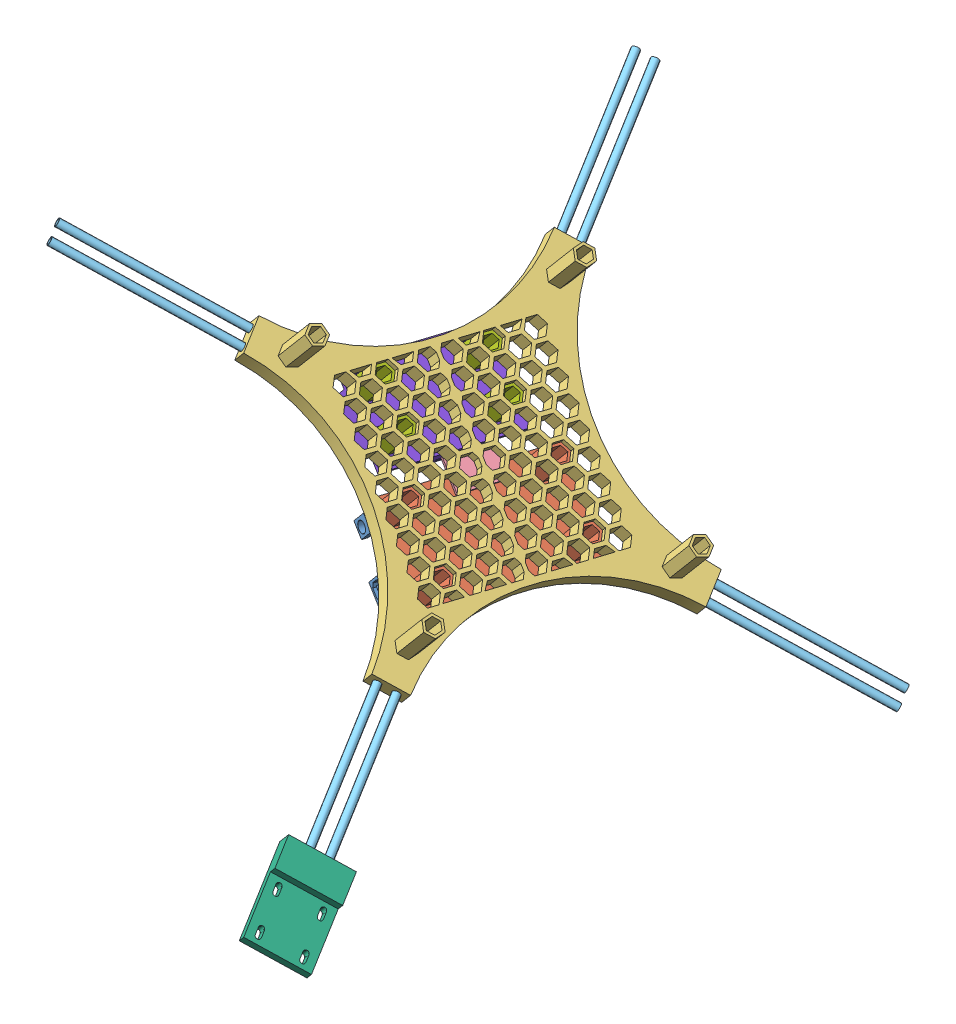
SolidWorks assembly QUAD, configuration Default. Lengths in mm.
Overall size (301.05 238.4 417.1).
19 component instances, 9 part files, 49 mates.
Components (placement in the parent):
- ArduinoMega-1: ArduinoMega [Default] at (337.5166 278.1665 -277.373) x (-0.218735 0.068032 0.97341) z (0.651257 0.753048 0.093714) size (107.95 53.42 12.95)
- arduino_mounting-3: arduino_mounting [Default] at (347.3982 264.798 -221.0032) x (0.218735 -0.068032 -0.97341) z (0.651257 0.753048 0.093714) size (103.6 55.42 18.5)
- krop_test2-1: krop_test2 [Default] at (277.9678 359.392 -375.9096) x (0.726649 -0.654439 0.209025) z (-0.218735 0.068032 0.97341) size (183 40 183)
- gyro_mounting-1: gyro_mounting [Default] at (330.3641 298.6046 -267.5745) x (0.218735 -0.068032 -0.97341) z (0.726649 -0.654439 0.209025) size (25 6.5 18)
- esc_mounting-1: esc_mounting [Default] at (301.4602 334.7052 -340.7941) x (0.726649 -0.654439 0.209025) z (-0.218735 0.068032 0.97341) size (45.02 6 45.46) (hidden)
- carbonfiber_rod-1: carbonfiber_rod [Default] at (475.6624 198.5284 -403.7813) x (0.715923 0.638866 0.281613) z (0.201442 -0.575212 0.792813) size (4.5 115 4.5)
- carbonfiber_rod-2: carbonfiber_rod [Default] at (479.2539 194.3819 -395.4202) x (0.715923 0.638866 0.281613) z (0.201442 -0.575212 0.792813) size (4.5 115 4.5)
- carbonfiber_rod-3: carbonfiber_rod [Default] at (406.2467 220.1183 -94.8694) x (0.91357 0.339343 -0.224132) z (-0.19079 0.84434 0.500689) size (4.5 115 4.5)
- carbonfiber_rod-4: carbonfiber_rod [Default] at (412.9316 215.0097 -100.2745) x (0.91357 0.339343 -0.224132) z (-0.19079 0.84434 0.500689) size (4.5 115 4.5)
- carbonfiber_rod-5: carbonfiber_rod [Default] at (259.2054 363.9466 -228.7662) x (0.715923 0.638866 0.281613) z (0.201442 -0.575212 0.792813) size (4.5 115 4.5)
- carbonfiber_rod-6: carbonfiber_rod [Default] at (262.7969 359.8001 -220.4051) x (0.715923 0.638866 0.281613) z (0.201442 -0.575212 0.792813) size (4.5 115 4.5)
- carbonfiber_rod-7: carbonfiber_rod [Default] at (289.9538 354.3832 -365.6019) x (0.91357 0.339343 -0.224132) z (-0.19079 0.84434 0.500689) size (4.5 115 4.5)
- carbonfiber_rod-8: carbonfiber_rod [Default] at (296.6387 349.2745 -371.0069) x (0.91357 0.339343 -0.224132) z (-0.19079 0.84434 0.500689) size (4.5 115 4.5)
- motor_mounting-1: motor_mounting [Default] at (403.8166 219.6624 -74.3174) x (-0.359149 0.414652 -0.836107) z (0.668488 -0.510864 -0.540502) size (53 10 35)
- ben_til_reciever_mounting-1: ben_til_reciever_mounting [Default] at (295.7926 314.9978 -260.4252) x (0.726649 -0.654439 0.209025) z (-0.218735 0.068032 0.97341) size (12.85 18 14.84)
- ben_til_reciever_mounting-2: ben_til_reciever_mounting [Default] at (277.2873 331.6642 -265.7483) x (0.726649 -0.654439 0.209025) z (-0.218735 0.068032 0.97341) size (12.85 18 14.84)
- ben_til_reciever_mounting-3: ben_til_reciever_mounting [Default] at (308.0725 311.1785 -315.0728) x (0.726649 -0.654439 0.209025) z (-0.218735 0.068032 0.97341) size (12.85 18 14.84)
- ben_til_reciever_mounting-4: ben_til_reciever_mounting [Default] at (289.5672 327.8448 -320.3959) x (0.726649 -0.654439 0.209025) z (-0.218735 0.068032 0.97341) size (12.85 18 14.84)
- reciever_mouting_til_pring-1: reciever_mouting_til_pring [Default] at (265.6062 341.3641 -258.2482) x (0.218735 -0.068032 -0.97341) z (-0.726649 0.654439 -0.209025) size (78.5 12.5 52)
Mates (geometry in assembly coordinates):
- Coincident5: coincident anti-aligned: plane of ArduinoMega-1 through (308.0726 300.3446 -233.3517) normal (0.651257 0.753048 0.093714); plane of arduino_mounting-3 through (347.3982 264.798 -221.0032) normal (-0.651257 -0.753048 -0.093714)
- Distance3: distance = 1 mm: line of ArduinoMega-1 through (329.5183 293.6744 -328.7887) axis (-0.218735 0.068032 0.97341); line of arduino_mounting-3 through (329.7883 294.0189 -333.4325) axis (-0.218735 0.068032 0.97341)
- Distance4: distance = 1 mm: line of ArduinoMega-1 through (358.0369 268.4485 -324.2703) axis (-0.726649 0.654439 -0.209025); line of arduino_mounting-3 through (370.0591 257.7499 -321.8484) axis (-0.726649 0.654439 -0.209025)
- Parallel3: parallel anti-aligned: line of arduino_mounting-3 through (348.375 265.9276 -220.8626) axis (0.218735 -0.068032 -0.97341); line of krop_test2-1 through (361.0536 275.7498 -281.1911) axis (-0.218735 0.068032 0.97341)
- Coincident16: coincident anti-aligned: plane of arduino_mounting-3 through (354.8876 273.4581 -219.9254) normal (0.651257 0.753048 0.093714); plane of krop_test2-1 through (204.8349 415.2808 -316.7784) normal (-0.651257 -0.753048 -0.093714)
- Coincident17: coincident anti-aligned: plane of arduino_mounting-3 through (326.8517 308.9478 -235.5785) normal (0.173894 -0.268302 0.94751); plane of krop_test2-1 through (326.7379 300.0613 -238.074) normal (-0.173894 0.268302 -0.94751)
- Coincident19: coincident anti-aligned: plane of arduino_mounting-3 through (323.7598 312.1159 -239.5493) normal (-0.552755 0.386137 0.738485); plane of krop_test2-1 through (322.2929 303.6765 -236.2345) normal (0.552755 -0.386137 -0.738485)
- Coincident26: coincident anti-aligned: plane of krop_test2-1 through (204.8349 415.2808 -316.7784) normal (-0.651257 -0.753048 -0.093714); plane of gyro_mounting-1 through (331.3409 299.7341 -267.434) normal (0.651257 0.753048 0.093714)
- Parallel5: parallel aligned: line of krop_test2-1 through (329.247 303.381 -282.1875) axis (-0.726649 0.654439 -0.209025); line of gyro_mounting-1 through (335.8324 296.9038 -291.9098) axis (-0.726649 0.654439 -0.209025)
- Coincident31: coincident anti-aligned: plane of krop_test2-1 through (324.9028 305.5925 -269.7678) normal (-0.173894 0.268302 -0.94751); plane of gyro_mounting-1 through (333.7447 304.8148 -271.6107) normal (0.173894 -0.268302 0.94751)
- Coincident32: coincident anti-aligned: plane of krop_test2-1 through (321.7741 308.7983 -273.7859) normal (0.552755 -0.386137 -0.738485); plane of gyro_mounting-1 through (332.3324 305.0815 -263.9396) normal (-0.552755 0.386137 0.738485)
- Coincident44: coincident anti-aligned: plane of krop_test2-1 through (300.1721 335.1058 -335.0617) normal (0.552755 -0.386137 -0.738485); plane of esc_mounting-1 through (300.3665 342.0084 -338.5254) normal (-0.552755 0.386137 0.738485)
- Coincident46: coincident anti-aligned: plane of krop_test2-1 through (304.617 331.4906 -336.9012) normal (-0.173894 0.268302 -0.94751); plane of esc_mounting-1 through (303.4284 338.8711 -334.5932) normal (0.173894 -0.268302 0.94751)
- Coincident47: coincident anti-aligned: plane of krop_test2-1 through (204.8349 415.2808 -316.7784) normal (-0.651257 -0.753048 -0.093714); plane of esc_mounting-1 through (301.4602 334.7052 -340.7941) normal (0.651257 0.753048 0.093714)
- Concentric1: concentric aligned: cylinder of krop_test2-1 through (398.7864 257.2777 -341.6236) axis (0.668488 -0.510864 -0.540502) radius 2.25; cylinder of carbonfiber_rod-1 through (398.7864 257.2777 -341.6236) axis (0.668488 -0.510864 -0.540502) radius 2.25
- Coincident48: coincident anti-aligned: plane of krop_test2-1 through (400.9173 247.2927 -329.5505) normal (0.668488 -0.510864 -0.540502); plane of carbonfiber_rod-1 through (398.7864 257.2777 -341.6236) normal (-0.668488 0.510864 0.540502)
- Concentric2: concentric aligned: cylinder of krop_test2-1 through (402.3778 253.1312 -333.2625) axis (0.668488 -0.510864 -0.540502) radius 2.25; cylinder of carbonfiber_rod-2 through (402.3778 253.1312 -333.2625) axis (0.668488 -0.510864 -0.540502) radius 2.25
- Coincident50: coincident anti-aligned: plane of krop_test2-1 through (400.9173 247.2927 -329.5505) normal (0.668488 -0.510864 -0.540502); plane of carbonfiber_rod-2 through (402.3778 253.1312 -333.2625) normal (-0.668488 0.510864 0.540502)
- Concentric3: concentric aligned: cylinder of krop_test2-1 through (364.9445 267.8033 -191.0218) axis (0.359149 -0.414652 0.836107) radius 2.25; cylinder of carbonfiber_rod-3 through (364.9445 267.8033 -191.0218) axis (0.359149 -0.414652 0.836107) radius 2.25
- Coincident51: coincident anti-aligned: plane of krop_test2-1 through (358.3458 266.5924 -188.7878) normal (0.359149 -0.414652 0.836107); plane of carbonfiber_rod-3 through (364.9445 267.8033 -191.0218) normal (-0.359149 0.414652 -0.836107)
- Concentric4: concentric aligned: cylinder of krop_test2-1 through (371.6294 262.6947 -196.4268) axis (0.359149 -0.414652 0.836107) radius 2.25; cylinder of carbonfiber_rod-4 through (371.6294 262.6947 -196.4268) axis (0.359149 -0.414652 0.836107) radius 2.25
- Coincident52: coincident anti-aligned: plane of krop_test2-1 through (358.3458 266.5924 -188.7878) normal (0.359149 -0.414652 0.836107); plane of carbonfiber_rod-4 through (371.6294 262.6947 -196.4268) normal (-0.359149 0.414652 -0.836107)
- Concentric5: concentric anti-aligned: cylinder of krop_test2-1 through (259.2054 363.9466 -228.7662) axis (-0.668488 0.510864 0.540502) radius 2.25; cylinder of carbonfiber_rod-5 through (182.3293 422.696 -166.6085) axis (0.668488 -0.510864 -0.540502) radius 2.25
- Coincident53: coincident anti-aligned: plane of krop_test2-1 through (254.1534 362.2547 -233.4153) normal (-0.668488 0.510864 0.540502); plane of carbonfiber_rod-5 through (259.2054 363.9466 -228.7662) normal (0.668488 -0.510864 -0.540502)
- Concentric6: concentric anti-aligned: cylinder of krop_test2-1 through (262.7969 359.8001 -220.4051) axis (-0.668488 0.510864 0.540502) radius 2.25; cylinder of carbonfiber_rod-6 through (185.9208 418.5495 -158.2474) axis (0.668488 -0.510864 -0.540502) radius 2.25
- Coincident54: coincident anti-aligned: plane of krop_test2-1 through (254.1534 362.2547 -233.4153) normal (-0.668488 0.510864 0.540502); plane of carbonfiber_rod-6 through (262.7969 359.8001 -220.4051) normal (0.668488 -0.510864 -0.540502)
- Concentric7: concentric anti-aligned: cylinder of krop_test2-1 through (296.6387 349.2745 -371.0069) axis (-0.359149 0.414652 -0.836107) radius 2.25; cylinder of carbonfiber_rod-8 through (255.3365 396.9595 -467.1593) axis (0.359149 -0.414652 0.836107) radius 2.25
- Coincident55: coincident anti-aligned: plane of krop_test2-1 through (296.7248 342.955 -374.178) normal (-0.359149 0.414652 -0.836107); plane of carbonfiber_rod-8 through (296.6387 349.2745 -371.0069) normal (0.359149 -0.414652 0.836107)
- Concentric8: concentric anti-aligned: cylinder of krop_test2-1 through (289.9538 354.3832 -365.6019) axis (-0.359149 0.414652 -0.836107) radius 2.25; cylinder of carbonfiber_rod-7 through (248.6517 402.0682 -461.7542) axis (0.359149 -0.414652 0.836107) radius 2.25
- Coincident56: coincident anti-aligned: plane of krop_test2-1 through (296.7248 342.955 -374.178) normal (-0.359149 0.414652 -0.836107); plane of carbonfiber_rod-7 through (289.9538 354.3832 -365.6019) normal (0.359149 -0.414652 0.836107)
- Coincident58: coincident anti-aligned: plane of krop_test2-1 through (204.8349 415.2808 -316.7784) normal (-0.651257 -0.753048 -0.093714); plane of ben_til_reciever_mounting-1 through (302.9565 323.2813 -259.3943) normal (0.651257 0.753048 0.093714)
- Coincident59: coincident anti-aligned: plane of krop_test2-1 through (306.0183 320.144 -255.4621) normal (-0.726649 0.654439 -0.209025); plane of ben_til_reciever_mounting-1 through (311.2212 325.215 -257.6723) normal (0.726649 -0.654439 0.209025)
- Coincident60: coincident anti-aligned: plane of krop_test2-1 through (301.5733 323.7592 -253.6226) normal (-0.173894 0.268302 -0.94751); plane of ben_til_reciever_mounting-1 through (308.4021 327.1843 -253.906) normal (0.173894 -0.268302 0.94751)
- Coincident61: coincident anti-aligned: plane of krop_test2-1 through (204.8349 415.2808 -316.7784) normal (-0.651257 -0.753048 -0.093714); plane of ben_til_reciever_mounting-2 through (284.4511 339.9477 -264.7175) normal (0.651257 0.753048 0.093714)
- Coincident62: coincident anti-aligned: plane of krop_test2-1 through (287.513 336.8104 -260.7853) normal (-0.726649 0.654439 -0.209025); plane of ben_til_reciever_mounting-2 through (292.7159 341.8814 -262.9955) normal (0.726649 -0.654439 0.209025)
- Coincident63: coincident anti-aligned: plane of krop_test2-1 through (283.068 340.4256 -258.9458) normal (-0.173894 0.268302 -0.94751); plane of ben_til_reciever_mounting-2 through (289.8968 343.8507 -259.2292) normal (0.173894 -0.268302 0.94751)
- Coincident64: coincident anti-aligned: plane of krop_test2-1 through (204.8349 415.2808 -316.7784) normal (-0.651257 -0.753048 -0.093714); plane of ben_til_reciever_mounting-3 through (315.2364 319.462 -314.0419) normal (0.651257 0.753048 0.093714)
- Coincident65: coincident anti-aligned: plane of krop_test2-1 through (319.6145 315.9153 -315.9673) normal (-0.726649 0.654439 -0.209025); plane of ben_til_reciever_mounting-3 through (323.5011 321.3957 -312.3199) normal (0.726649 -0.654439 0.209025)
- Coincident66: coincident anti-aligned: plane of krop_test2-1 through (318.2982 316.3247 -310.1097) normal (-0.173894 0.268302 -0.94751); plane of ben_til_reciever_mounting-3 through (320.682 323.365 -308.5536) normal (0.173894 -0.268302 0.94751)
- Coincident67: coincident anti-aligned: plane of krop_test2-1 through (204.8349 415.2808 -316.7784) normal (-0.651257 -0.753048 -0.093714); plane of ben_til_reciever_mounting-4 through (296.731 336.1284 -319.3651) normal (0.651257 0.753048 0.093714)
- Coincident68: coincident anti-aligned: plane of krop_test2-1 through (301.1091 332.5817 -321.2904) normal (-0.726649 0.654439 -0.209025); plane of ben_til_reciever_mounting-4 through (304.9957 338.0621 -317.6431) normal (0.726649 -0.654439 0.209025)
- Coincident69: coincident anti-aligned: plane of krop_test2-1 through (299.7929 332.9911 -315.4329) normal (-0.173894 0.268302 -0.94751); plane of ben_til_reciever_mounting-4 through (302.1767 340.0314 -313.8768) normal (0.173894 -0.268302 0.94751)
- Coincident71: coincident anti-aligned: plane of ben_til_reciever_mounting-3 through (308.0725 311.1785 -315.0728) normal (-0.651257 -0.753048 -0.093714); plane of reciever_mouting_til_pring-1 through (265.3457 341.0629 -258.2857) normal (0.651257 0.753048 0.093714)
- Parallel6: parallel anti-aligned: line of ben_til_reciever_mounting-3 through (311.9299 307.2261 -310.119) axis (0.218735 -0.068032 -0.97341); line of reciever_mouting_til_pring-1 through (307.0682 303.8009 -271.2184) axis (-0.218735 0.068032 0.97341)
- Coincident74: coincident anti-aligned: plane of ben_til_reciever_mounting-3 through (307.7523 313.1893 -307.6637) normal (0.173894 -0.268302 0.94751); plane of reciever_mouting_til_pring-1 through (312.4203 306.8272 -310.3219) normal (-0.173894 0.268302 -0.94751)
- Coincident75: coincident anti-aligned: plane of ben_til_reciever_mounting-3 through (303.8949 317.1417 -312.6175) normal (-0.552755 0.386137 0.738485); plane of reciever_mouting_til_pring-1 through (306.4497 311.6832 -307.8511) normal (0.552755 -0.386137 -0.738485)
- Concentric9: concentric anti-aligned: cylinder of carbonfiber_rod-4 through (371.6294 262.6947 -196.4268) axis (0.359149 -0.414652 0.836107) radius 2.25; cylinder of motor_mounting-1 through (412.9316 215.0097 -100.2745) axis (-0.359149 0.414652 -0.836107) radius 2.25
- Concentric10: concentric anti-aligned: cylinder of carbonfiber_rod-3 through (364.9445 267.8033 -191.0218) axis (0.359149 -0.414652 0.836107) radius 2.25; cylinder of motor_mounting-1 through (406.2467 220.1183 -94.8694) axis (-0.359149 0.414652 -0.836107) radius 2.25
- Coincident81: coincident anti-aligned: plane of carbonfiber_rod-3 through (406.2467 220.1183 -94.8694) normal (0.359149 -0.414652 0.836107); plane of motor_mounting-1 through (406.2467 220.1183 -94.8694) normal (-0.359149 0.414652 -0.836107)
